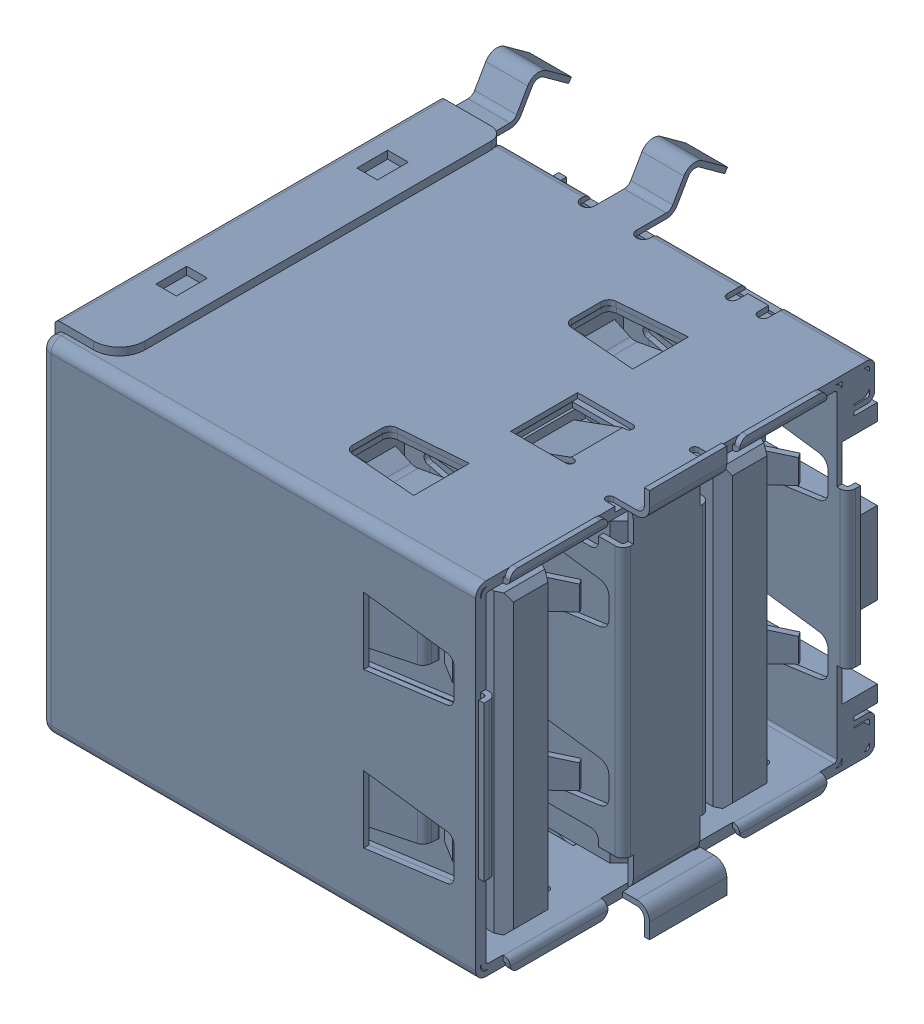
SolidWorks assembly USB_Ports_4,5_USB1, configuration Default. Lengths in mm.
Overall size (18 15.6 18.75).
2 component instances, 1 part files, 0 mates.
Components (placement in the parent):
- 672984090-1: 672984090 [Default] at (183.97 39.3699 8) x (0 1 0) z (1 0 0) size (15.6 18.75 18)
  - Open CASCADE STEP translator 6.2 1.82.1.1-1: Open CASCADE STEP translator 6.2 1.82.1.1 [Default] at origin size (15.6 18.75 18)
